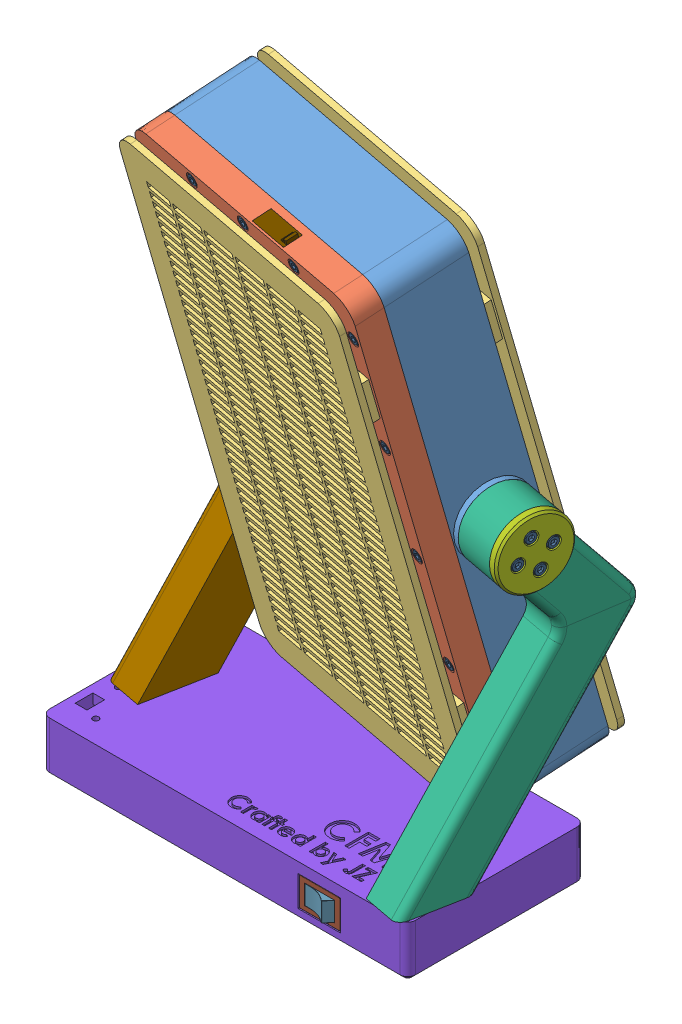
SolidWorks assembly assm, configuration Default. Lengths in mm.
Overall size (203.65 301.44 157.63).
57 component instances, 21 part files, 88 mates.
Components (placement in the parent):
- body-1: body [Default] at (119.8439 173.8656 72.5673) x (0.982382 0 0.186882) z (-0.180853 -0.251949 0.950691) size (182 260 42)
- cap-1: cap [Default] at (110.6204 161.0162 121.0525) x (-0.982382 0 -0.186882) z (0.180853 0.251949 -0.950691) size (140 260 13)
- cover-1: cover [Default] at (109.897 160.0084 124.8553) x (0.982382 0 0.186882) z (-0.180853 -0.251949 0.950691) size (140 260 12)
- Fan_120x120x38.step-1: Fan_120x120x38.step [Default] at (117.4629 232.8978 87.7588) x (0.982382 0 0.186882) z (-0.180853 -0.251949 0.950691) size (120 120 43.47)
  - Propeller.step-1: Propeller.step [Default] at (0 0 14.5) size (112.33 112.13 17.05)
  - Screws.step-1: Screws.step [Default] at origin size (116.5 116.5 11.47) (hidden)
  - LabelString.step-1: LabelString.step [Default] at origin size (29.77 5.26 0.01) (hidden)
  - Label.step-1: Label.step [Default] at origin size (38.43 38.43 0.1) (hidden)
  - Frame.step-1: Frame.step [Default] at origin size (120 120 38)
- Fan_120x120x38.step-2: Fan_120x120x38.step [Default] at (123.1131 116.7689 58.0576) x (0.982382 0 0.186882) z (-0.180853 -0.251949 0.950691) size (120 120 43.47)
  - Propeller.step-1: Propeller.step [Default] at (0 0 14.5) size (112.33 112.13 17.05)
  - Screws.step-1: Screws.step [Default] at origin size (116.5 116.5 11.47) (hidden)
  - LabelString.step-1: LabelString.step [Default] at origin size (29.77 5.26 0.01) (hidden)
  - Label.step-1: Label.step [Default] at origin size (38.43 38.43 0.1) (hidden)
  - Frame.step-1: Frame.step [Default] at origin size (120 120 38)
- side_bar-1: side_bar [Default] at (197.7646 26 107.0923) x (0.982382 0 0.186882) z (-0.186882 0 0.982382) size (20.38 160.33 105.41)
- tensioner-1: tensioner [Default] at (207.5884 168.8267 108.9611) x (0.180853 0.251949 -0.950691) z (0.982382 0 0.186882) size (35 35 4.6)
- bottom_upper-1: bottom_upper [Default] at (106.2737 0 117.6606) x (1 0 0) z (0 1 0) size (186 94 26)
- side_bar_irror-1: side_bar_irror [Default] at (34.6891 26 76.0699) x (0.982382 0 0.186882) z (-0.186882 0 0.982382) size (20.38 160.33 105.41)
- cover-2: cover [Default] at (120.5673 174.8734 68.7645) x (-0.982382 0 -0.186882) z (0.180853 0.251949 -0.950691) size (140 260 12)
- tensioner-2: tensioner [Default] at (24.8653 168.8267 74.2011) x (0.047085 -0.967741 -0.24751) z (-0.982382 0 -0.186882) size (35 35 4.6)
- socket head cap screw_am-5: socket head cap screw_am [B18.3.1M - 3 x 0.5 x 65 Hex SHCS -- 18NHX] at (19.4889 166.8111 81.0591) x (0.982382 0 0.186882) z (-0.179429 0.27958 0.943207) size (68 5.5 5.5)
- socket head cap screw_am-6: socket head cap screw_am [B18.3.1M - 3 x 0.5 x 65 Hex SHCS -- 18NHX] at (21.3124 161.0847 71.4735) x (0.982382 0 0.186882) z (-0.179429 0.27958 0.943207) size (68 5.5 5.5)
- socket head cap screw_am-7: socket head cap screw_am [B18.3.1M - 3 x 0.5 x 65 Hex SHCS -- 18NHX] at (22.3826 170.8422 65.8481) x (0.982382 0 0.186882) z (-0.179429 0.27958 0.943207) size (68 5.5 5.5)
- socket head cap screw_am-8: socket head cap screw_am [B18.3.1M - 3 x 0.5 x 65 Hex SHCS -- 18NHX] at (20.5591 176.5686 75.4337) x (0.982382 0 0.186882) z (-0.179429 0.27958 0.943207) size (68 5.5 5.5)
- socket head cap screw_am-9: socket head cap screw_am [B18.3.1M - 3 x 0.5 x 5 Hex SHCS -- 5NHX] at (211.1413 176.5686 111.6887) x (-0.982382 0 -0.186882) z (0.179429 -0.27958 -0.943207) size (8 5.5 5.5)
- socket head cap screw_am-10: socket head cap screw_am [B18.3.1M - 3 x 0.5 x 5 Hex SHCS -- 5NHX] at (212.9648 170.8422 102.1031) x (-0.982382 0 -0.186882) z (0.179429 -0.27958 -0.943207) size (8 5.5 5.5)
- socket head cap screw_am-11: socket head cap screw_am [B18.3.1M - 3 x 0.5 x 5 Hex SHCS -- 5NHX] at (211.8946 161.0847 107.7285) x (-0.982382 0 -0.186882) z (0.179429 -0.27958 -0.943207) size (8 5.5 5.5)
- socket head cap screw_am-12: socket head cap screw_am [B18.3.1M - 3 x 0.5 x 5 Hex SHCS -- 5NHX] at (210.0711 166.8111 117.3142) x (-0.982382 0 -0.186882) z (0.179429 -0.27958 -0.943207) size (8 5.5 5.5)
- socket head cap screw_am-13: socket head cap screw_am [B18.3.1M - 3 x 0.5 x 12 Hex SHCS -- 12NHX] at (72.8074 281.9838 145.9177) x (0.180853 0.251949 -0.950691) z (0.98351 -0.045912 0.174929) size (15 5.5 5.5)
- socket head cap screw_am-14: socket head cap screw_am [B18.3.1M - 3 x 0.5 x 12 Hex SHCS -- 12NHX] at (104.7348 281.9838 151.9913) x (0.180853 0.251949 -0.950691) z (0.98351 -0.045912 0.174929) size (15 5.5 5.5)
- socket head cap screw_am-15: socket head cap screw_am [B18.3.1M - 3 x 0.5 x 12 Hex SHCS -- 12NHX] at (136.6623 281.9838 158.065) x (0.180853 0.251949 -0.950691) z (0.98351 -0.045912 0.174929) size (15 5.5 5.5)
- socket head cap screw_am-16: socket head cap screw_am [B18.3.1M - 3 x 0.5 x 12 Hex SHCS -- 12NHX] at (169.296 267.4677 160.426) x (0.180853 0.251949 -0.950691) z (0.98351 -0.045912 0.174929) size (15 5.5 5.5)
- socket head cap screw_am-17: socket head cap screw_am [B18.3.1M - 3 x 0.5 x 12 Hex SHCS -- 12NHX] at (171.8856 214.242 146.8129) x (0.180853 0.251949 -0.950691) z (0.98351 -0.045912 0.174929) size (15 5.5 5.5)
- socket head cap screw_am-18: socket head cap screw_am [B18.3.1M - 3 x 0.5 x 12 Hex SHCS -- 12NHX] at (174.4753 161.0162 133.1998) x (0.180853 0.251949 -0.950691) z (0.98351 -0.045912 0.174929) size (15 5.5 5.5)
- socket head cap screw_am-19: socket head cap screw_am [B18.3.1M - 3 x 0.5 x 12 Hex SHCS -- 12NHX] at (177.0649 107.7905 119.5868) x (0.180853 0.251949 -0.950691) z (0.98351 -0.045912 0.174929) size (15 5.5 5.5)
- socket head cap screw_am-20: socket head cap screw_am [B18.3.1M - 3 x 0.5 x 12 Hex SHCS -- 12NHX] at (179.6546 54.5648 105.9737) x (0.180853 0.251949 -0.950691) z (0.98351 -0.045912 0.174929) size (15 5.5 5.5)
- socket head cap screw_am-21: socket head cap screw_am [B18.3.1M - 3 x 0.5 x 12 Hex SHCS -- 12NHX] at (148.4334 40.0487 96.1874) x (0.180853 0.251949 -0.950691) z (0.98351 -0.045912 0.174929) size (15 5.5 5.5)
- socket head cap screw_am-22: socket head cap screw_am [B18.3.1M - 3 x 0.5 x 12 Hex SHCS -- 12NHX] at (116.506 40.0487 90.1138) x (0.180853 0.251949 -0.950691) z (0.98351 -0.045912 0.174929) size (15 5.5 5.5)
- socket head cap screw_am-23: socket head cap screw_am [B18.3.1M - 3 x 0.5 x 12 Hex SHCS -- 12NHX] at (84.5785 40.0487 84.0401) x (0.180853 0.251949 -0.950691) z (0.98351 -0.045912 0.174929) size (15 5.5 5.5)
- socket head cap screw_am-24: socket head cap screw_am [B18.3.1M - 3 x 0.5 x 12 Hex SHCS -- 12NHX] at (51.9449 54.5648 81.6791) x (0.180853 0.251949 -0.950691) z (0.98351 -0.045912 0.174929) size (15 5.5 5.5)
- socket head cap screw_am-25: socket head cap screw_am [B18.3.1M - 3 x 0.5 x 12 Hex SHCS -- 12NHX] at (49.3552 107.7905 95.2922) x (0.180853 0.251949 -0.950691) z (0.98351 -0.045912 0.174929) size (15 5.5 5.5)
- socket head cap screw_am-26: socket head cap screw_am [B18.3.1M - 3 x 0.5 x 12 Hex SHCS -- 12NHX] at (46.7655 161.0162 108.9052) x (0.180853 0.251949 -0.950691) z (0.98351 -0.045912 0.174929) size (15 5.5 5.5)
- socket head cap screw_am-27: socket head cap screw_am [B18.3.1M - 3 x 0.5 x 12 Hex SHCS -- 12NHX] at (44.1759 214.242 122.5183) x (0.180853 0.251949 -0.950691) z (0.98351 -0.045912 0.174929) size (15 5.5 5.5)
- socket head cap screw_am-28: socket head cap screw_am [B18.3.1M - 3 x 0.5 x 12 Hex SHCS -- 12NHX] at (41.5862 267.4677 136.1314) x (0.180853 0.251949 -0.950691) z (0.98351 -0.045912 0.174929) size (15 5.5 5.5)
- socket head cap screw_am-29: socket head cap screw_am [B18.3.1M - 3 x 0.5 x 12 Hex SHCS -- 12NHX] at (90.9728 161.0162 117.3149) x (0.180853 0.251949 -0.950691) z (0.98351 -0.045912 0.174929) size (15 5.5 5.5)
- socket head cap screw_am-30: socket head cap screw_am [B18.3.1M - 3 x 0.5 x 12 Hex SHCS -- 12NHX] at (130.2681 161.0162 124.7902) x (0.180853 0.251949 -0.950691) z (0.98351 -0.045912 0.174929) size (15 5.5 5.5)
- Power Switch.step-1: Power Switch.step [Default] at (143.8457 5.541 160.3606) x (1 0 0) z (0 -1 0) size (21.33 24.14 14.86)
  - Power Switch1.STEP-1: Power Switch1.STEP [Default] at origin size (21.33 13.56 14.86)
  - Power Switch2.STEP-1: Power Switch2.STEP [Default] at origin size (0.83 7.82 7.65)
  - Power Switch3.STEP-1: Power Switch3.STEP [Default] at origin size (0.83 7.82 7.65)
  - Power Switch4.STEP-1: Power Switch4.STEP [Default] at origin size (15.06 5.51 9.8)
- Fuse.step-1: Fuse.step [Default] at (159.2737 13 88.8606) x (-0.999964 -0.008477 0) z (0 0 -1) size (15 15.01 38.3)
  - Fuse1.STEP-1: Fuse1.STEP [Default] at origin size (4 2.2 7.9)
  - Fuse2.STEP-1: Fuse2.STEP [Default] at origin size (15 15.01 38.3)
- cable-1: cable [Default] at (33.2737 13 68.6606) size (39.97 7 53.33)
- carbon_filling_cap-1: carbon_filling_cap [Default] at (121.7053 287.1775 151.0738) x (-0.982382 0 -0.186882) z (-0.047085 0.967741 0.24751) size (23.5 8.5 11.9)
Mates (geometry in assembly coordinates):
- Concentric1: concentric aligned: cylinder of body-1 through (172.0811 271.3477 145.7853) axis (-0.180853 -0.251949 0.950691) radius 2.2; cylinder of cap-1 through (169.296 267.4677 160.426) axis (-0.180853 -0.251949 0.950691) radius 3.25
- Concentric2: concentric aligned: cylinder of body-1 through (54.73 58.4448 67.0385) axis (-0.180853 -0.251949 0.950691) radius 2.2; cylinder of cap-1 through (51.9449 54.5648 81.6791) axis (-0.180853 -0.251949 0.950691) radius 3.25
- Coincident1: coincident aligned: plane of cap-1 through (187.1358 37.4775 93.4017) normal (0.982382 0 0.186882); plane of cover-1 through (183.1571 31.9346 114.3169) normal (0.982382 0 0.186882)
- Coincident2: coincident aligned: plane of cap-1 through (174.8939 289.0901 157.7543) normal (-0.047085 0.967741 0.24751); plane of cover-1 through (33.3816 283.5472 152.5061) normal (-0.047085 0.967741 0.24751)
- Coincident5: coincident anti-aligned: plane of body-1 through (47.1167 280.3804 131.1387) normal (0.047085 -0.967741 -0.24751); plane of Fan_120x120x38.step-1/Frame.step-1 through (111.1874 286.1553 120.7477) normal (-0.047085 0.967741 0.24751)
- Coincident6: coincident anti-aligned: plane of body-1 through (165.985 280.3804 153.7514) normal (-0.982382 0 -0.186882); plane of Fan_120x120x38.step-1/Frame.step-1 through (172.9554 228.0909 117.1099) normal (0.982382 0 0.186882)
- Coincident7: coincident anti-aligned: plane of body-1 through (112.9715 164.2916 108.6936) normal (0.180853 0.251949 -0.950691); plane of Fan_120x120x38.step-1/Frame.step-1 through (110.5905 223.3238 123.8851) normal (-0.180853 -0.251949 0.950691)
- Coincident8: coincident anti-aligned: plane of cap-1 through (110.6204 161.0162 121.0525) normal (-0.180853 -0.251949 0.950691); plane of cover-1 through (173.291 249.9516 156.5439) normal (0.180853 0.251949 -0.950691)
- Concentric7: concentric anti-aligned: cylinder of body-1 through (205.6236 168.8267 108.5873) axis (-0.982382 0 -0.186882) radius 12; cylinder of side_bar-1 through (187.9408 168.8267 105.2235) axis (0.982382 0 0.186882) radius 17.5
- Coincident9: coincident anti-aligned: plane of body-1 through (187.9408 168.8267 105.2235) normal (0.982382 0 0.186882); plane of side_bar-1 through (188.8609 185.6198 100.3868) normal (-0.982382 0 -0.186882)
- Concentric9: concentric aligned: cylinder of body-1 through (198.3703 176.5686 109.2592) axis (0.982382 0 0.186882) radius 2.2; cylinder of tensioner-1 through (211.1413 176.5686 111.6887) axis (0.982382 0 0.186882) radius 3.25
- Concentric10: concentric aligned: cylinder of body-1 through (199.1236 161.0847 105.2991) axis (0.982382 0 0.186882) radius 2.2; cylinder of tensioner-1 through (211.8946 161.0847 107.7285) axis (0.982382 0 0.186882) radius 3.25
- Coincident10: coincident anti-aligned: plane of side_bar-1 through (208.5085 185.6198 104.1244) normal (0.982382 0 0.186882); plane of tensioner-1 through (207.5884 168.8267 108.9611) normal (-0.982382 0 -0.186882)
- Coincident11: coincident anti-aligned: plane of body-1 through (177.5646 48.1627 90.2052) normal (-0.180853 -0.251949 0.950691); plane of cap-1 through (177.5646 48.1627 90.2052) normal (0.180853 0.251949 -0.950691)
- Concentric13: concentric aligned: cylinder of side_bar-1 through (183.2737 32.5 151.1606) axis (0 -1 0) radius 2.2; cylinder of bottom_upper-1 through (183.2737 21 151.1606) axis (0 -1 0) radius 1.5
- Coincident13: coincident anti-aligned: plane of side_bar-1 through (197.7646 26 107.0923) normal (0 -1 0); plane of bottom_upper-1 through (106.2737 26 117.6606) normal (0 1 0)
- Concentric15: concentric: cylinder of body-1 through (26.83 168.8267 74.5749) axis (0.982382 0 0.186882) radius 12; cylinder of side_bar_irror-1 through (-8.6168 168.8267 67.8317) axis (0.982382 0 0.186882) radius 12.05
- Coincident14: coincident anti-aligned: plane of body-1 through (44.5129 168.8267 77.9388) normal (-0.982382 0 -0.186882); plane of side_bar_irror-1 through (45.433 185.6198 73.1021) normal (0.982382 0 0.186882)
- Coincident15: coincident anti-aligned: plane of bottom_upper-1 through (106.2737 26 117.6606) normal (0 1 0); plane of side_bar_irror-1 through (34.6891 26 76.0699) normal (0 -1 0)
- Coincident16: coincident anti-aligned: plane of body-1 through (119.8439 173.8656 72.5673) normal (0.180853 0.251949 -0.950691); plane of cover-2 through (182.5145 262.801 108.0586) normal (-0.180853 -0.251949 0.950691)
- Coincident17: coincident aligned: plane of body-1 through (37.3603 289.0901 131.5909) normal (-0.047085 0.967741 0.24751); plane of cover-2 through (184.8408 302.9472 105.4663) normal (-0.047085 0.967741 0.24751)
- Coincident18: coincident aligned: plane of body-1 through (174.8939 289.0901 157.7543) normal (0.982382 0 0.186882); plane of cover-2 through (197.0828 51.3347 41.1137) normal (0.982382 0 0.186882)
- Concentric16: concentric aligned: cylinder of body-1 through (33.33 176.5686 77.8631) axis (-0.982382 0 -0.186882) radius 2.2; cylinder of tensioner-2 through (20.5591 176.5686 75.4337) axis (-0.982382 0 -0.186882) radius 3.25
- Concentric17: concentric aligned: cylinder of body-1 through (34.0834 161.0847 73.903) axis (-0.982382 0 -0.186882) radius 2.2; cylinder of tensioner-2 through (21.3124 161.0847 71.4735) axis (-0.982382 0 -0.186882) radius 3.25
- Coincident19: coincident anti-aligned: plane of side_bar_irror-1 through (25.7854 185.6198 69.3644) normal (-0.982382 0 -0.186882); plane of tensioner-2 through (24.8653 168.8267 74.2011) normal (0.982382 0 0.186882)
- Concentric181: concentric aligned: cylinder of tensioner-2 through (19.4889 166.8111 81.0591) axis (-0.982382 0 -0.186882) radius 1.6; cylinder of socket head cap screw_am-5 through (-11.7017 166.8111 75.1256) axis (-0.982382 0 -0.186882) radius 1.5
- Coincident211: coincident anti-aligned: plane of tensioner-2 through (22.5114 165.2627 81.2238) normal (-0.982382 0 -0.186882); plane of socket head cap screw_am-5 through (22.5798 169.4514 80.8645) normal (0.982382 0 0.186882)
- Concentric191: concentric aligned: cylinder of tensioner-2 through (21.3124 161.0847 71.4735) axis (-0.982382 0 -0.186882) radius 1.6; cylinder of socket head cap screw_am-6 through (-9.8782 161.0847 65.54) axis (-0.982382 0 -0.186882) radius 1.5
- Coincident221: coincident anti-aligned: plane of tensioner-2 through (24.3349 159.5363 71.6382) normal (-0.982382 0 -0.186882); plane of socket head cap screw_am-6 through (24.4033 163.7251 71.2789) normal (0.982382 0 0.186882)
- Concentric201: concentric aligned: cylinder of tensioner-2 through (22.3826 170.8422 65.8481) axis (-0.982382 0 -0.186882) radius 1.6; cylinder of socket head cap screw_am-7 through (-8.8081 170.8422 59.9146) axis (-0.982382 0 -0.186882) radius 1.5
- Coincident231: coincident anti-aligned: plane of tensioner-2 through (25.4051 169.2939 66.0127) normal (-0.982382 0 -0.186882); plane of socket head cap screw_am-7 through (25.4734 173.4826 65.6534) normal (0.982382 0 0.186882)
- Concentric211: concentric aligned: cylinder of tensioner-2 through (20.5591 176.5686 75.4337) axis (-0.982382 0 -0.186882) radius 1.6; cylinder of socket head cap screw_am-8 through (-10.6316 176.5686 69.5002) axis (-0.982382 0 -0.186882) radius 1.5
- Coincident241: coincident anti-aligned: plane of tensioner-2 through (23.5816 175.0202 75.5983) normal (-0.982382 0 -0.186882); plane of socket head cap screw_am-8 through (23.6499 179.2089 75.239) normal (0.982382 0 0.186882)
- Concentric221: concentric aligned: cylinder of tensioner-1 through (211.1413 176.5686 111.6887) axis (0.982382 0 0.186882) radius 1.6; cylinder of socket head cap screw_am-9 through (242.3319 176.5686 117.6222) axis (0.982382 0 0.186882) radius 1.5
- Coincident251: coincident anti-aligned: plane of tensioner-1 through (208.4835 176.9717 109.607) normal (0.982382 0 0.186882); plane of socket head cap screw_am-9 through (208.3378 179.2089 110.3728) normal (-0.982382 0 -0.186882)
- Concentric231: concentric aligned: cylinder of tensioner-1 through (212.9648 170.8422 102.1031) axis (0.982382 0 0.186882) radius 1.6; cylinder of socket head cap screw_am-10 through (244.1554 170.8422 108.0366) axis (0.982382 0 0.186882) radius 1.5
- Coincident261: coincident anti-aligned: plane of tensioner-1 through (210.307 171.2454 100.0213) normal (0.982382 0 0.186882); plane of socket head cap screw_am-10 through (210.1613 173.4826 100.7872) normal (-0.982382 0 -0.186882)
- Concentric241: concentric aligned: cylinder of tensioner-1 through (211.8946 161.0847 107.7285) axis (0.982382 0 0.186882) radius 1.6; cylinder of socket head cap screw_am-11 through (243.0853 161.0847 113.662) axis (0.982382 0 0.186882) radius 1.5
- Coincident271: coincident anti-aligned: plane of tensioner-1 through (209.2368 161.4879 105.6468) normal (0.982382 0 0.186882); plane of socket head cap screw_am-11 through (209.0912 163.7251 106.4126) normal (-0.982382 0 -0.186882)
- Concentric251: concentric aligned: cylinder of tensioner-1 through (210.0711 166.8111 117.3142) axis (0.982382 0 0.186882) radius 1.6; cylinder of socket head cap screw_am-12 through (241.2618 166.8111 123.2476) axis (0.982382 0 0.186882) radius 1.5
- Coincident281: coincident anti-aligned: plane of tensioner-1 through (207.4133 167.2142 115.2324) normal (0.982382 0 0.186882); plane of socket head cap screw_am-12 through (207.2677 169.4514 115.9982) normal (-0.982382 0 -0.186882)
- Concentric261: concentric aligned: cylinder of cap-1 through (72.8074 281.9838 145.9177) axis (-0.180853 -0.251949 0.950691) radius 1.6; cylinder of socket head cap screw_am-13 through (67.0653 273.9844 176.1021) axis (-0.180853 -0.251949 0.950691) radius 1.5
- Coincident291: coincident anti-aligned: plane of cap-1 through (71.7781 282.7397 142.7666) normal (-0.180853 -0.251949 0.950691); plane of socket head cap screw_am-13 through (73.3488 285.3979 143.7699) normal (0.180853 0.251949 -0.950691)
- Concentric271: concentric aligned: cylinder of cap-1 through (104.7348 281.9838 151.9913) axis (-0.180853 -0.251949 0.950691) radius 1.6; cylinder of socket head cap screw_am-14 through (98.9928 273.9844 182.1758) axis (-0.180853 -0.251949 0.950691) radius 1.5
- Coincident301: coincident anti-aligned: plane of cap-1 through (103.7056 282.7397 148.8402) normal (-0.180853 -0.251949 0.950691); plane of socket head cap screw_am-14 through (105.2762 285.3979 149.8435) normal (0.180853 0.251949 -0.950691)
- Concentric281: concentric aligned: cylinder of cap-1 through (136.6623 281.9838 158.065) axis (-0.180853 -0.251949 0.950691) radius 1.6; cylinder of socket head cap screw_am-15 through (130.9202 273.9844 188.2494) axis (-0.180853 -0.251949 0.950691) radius 1.5
- Coincident311: coincident anti-aligned: plane of cap-1 through (135.633 282.7397 154.9139) normal (-0.180853 -0.251949 0.950691); plane of socket head cap screw_am-15 through (137.2037 285.3979 155.9172) normal (0.180853 0.251949 -0.950691)
- Concentric291: concentric aligned: cylinder of cap-1 through (169.296 267.4677 160.426) axis (-0.180853 -0.251949 0.950691) radius 1.6; cylinder of socket head cap screw_am-16 through (163.5539 259.4683 190.6104) axis (-0.180853 -0.251949 0.950691) radius 1.5
- Coincident321: coincident anti-aligned: plane of cap-1 through (168.2667 268.2236 157.2749) normal (-0.180853 -0.251949 0.950691); plane of socket head cap screw_am-16 through (169.8374 270.8818 158.2782) normal (0.180853 0.251949 -0.950691)
- Concentric301: concentric aligned: cylinder of cap-1 through (171.8856 214.242 146.8129) axis (-0.180853 -0.251949 0.950691) radius 1.6; cylinder of socket head cap screw_am-17 through (166.1435 206.2426 176.9974) axis (-0.180853 -0.251949 0.950691) radius 1.5
- Coincident331: coincident anti-aligned: plane of cap-1 through (170.8564 214.9978 143.6618) normal (-0.180853 -0.251949 0.950691); plane of socket head cap screw_am-17 through (172.427 217.6561 144.6651) normal (0.180853 0.251949 -0.950691)
- Concentric311: concentric aligned: cylinder of cap-1 through (174.4753 161.0162 133.1998) axis (-0.180853 -0.251949 0.950691) radius 1.6; cylinder of socket head cap screw_am-18 through (168.7332 153.0169 163.3843) axis (-0.180853 -0.251949 0.950691) radius 1.5
- Coincident341: coincident anti-aligned: plane of cap-1 through (173.446 161.7721 130.0488) normal (-0.180853 -0.251949 0.950691); plane of socket head cap screw_am-18 through (175.0167 164.4304 131.052) normal (0.180853 0.251949 -0.950691)
- Concentric321: concentric aligned: cylinder of cap-1 through (177.0649 107.7905 119.5868) axis (-0.180853 -0.251949 0.950691) radius 1.6; cylinder of socket head cap screw_am-19 through (171.3228 99.7911 149.7712) axis (-0.180853 -0.251949 0.950691) radius 1.5
- Coincident351: coincident anti-aligned: plane of cap-1 through (176.0357 108.5464 116.4357) normal (-0.180853 -0.251949 0.950691); plane of socket head cap screw_am-19 through (177.6063 111.2046 117.439) normal (0.180853 0.251949 -0.950691)
- Concentric331: concentric aligned: cylinder of cap-1 through (179.6546 54.5648 105.9737) axis (-0.180853 -0.251949 0.950691) radius 1.6; cylinder of socket head cap screw_am-20 through (173.9125 46.5654 136.1582) axis (-0.180853 -0.251949 0.950691) radius 1.5
- Coincident361: coincident anti-aligned: plane of cap-1 through (178.6253 55.3206 102.8227) normal (-0.180853 -0.251949 0.950691); plane of socket head cap screw_am-20 through (180.196 57.9789 103.8259) normal (0.180853 0.251949 -0.950691)
- Concentric341: concentric aligned: cylinder of cap-1 through (148.4334 40.0487 96.1874) axis (-0.180853 -0.251949 0.950691) radius 1.6; cylinder of socket head cap screw_am-21 through (142.6913 32.0493 126.3719) axis (-0.180853 -0.251949 0.950691) radius 1.5
- Coincident371: coincident anti-aligned: plane of cap-1 through (147.4042 40.8045 93.0364) normal (-0.180853 -0.251949 0.950691); plane of socket head cap screw_am-21 through (148.9748 43.4628 94.0396) normal (0.180853 0.251949 -0.950691)
- Concentric351: concentric aligned: cylinder of cap-1 through (116.506 40.0487 90.1138) axis (-0.180853 -0.251949 0.950691) radius 1.6; cylinder of socket head cap screw_am-22 through (110.7639 32.0493 120.2982) axis (-0.180853 -0.251949 0.950691) radius 1.5
- Coincident381: coincident anti-aligned: plane of cap-1 through (115.4767 40.8045 86.9627) normal (-0.180853 -0.251949 0.950691); plane of socket head cap screw_am-22 through (117.0474 43.4628 87.966) normal (0.180853 0.251949 -0.950691)
- Concentric361: concentric aligned: cylinder of cap-1 through (84.5785 40.0487 84.0401) axis (-0.180853 -0.251949 0.950691) radius 1.6; cylinder of socket head cap screw_am-23 through (78.8365 32.0493 114.2246) axis (-0.180853 -0.251949 0.950691) radius 1.5
- Coincident391: coincident anti-aligned: plane of cap-1 through (83.5493 40.8045 80.8891) normal (-0.180853 -0.251949 0.950691); plane of socket head cap screw_am-23 through (85.1199 43.4628 81.8923) normal (0.180853 0.251949 -0.950691)
- Concentric371: concentric aligned: cylinder of cap-1 through (51.9449 54.5648 81.6791) axis (-0.180853 -0.251949 0.950691) radius 1.6; cylinder of socket head cap screw_am-24 through (46.2028 46.5654 111.8636) axis (-0.180853 -0.251949 0.950691) radius 1.5
- Coincident401: coincident anti-aligned: plane of cap-1 through (50.9156 55.3206 78.5281) normal (-0.180853 -0.251949 0.950691); plane of socket head cap screw_am-24 through (52.4862 57.9789 79.5313) normal (0.180853 0.251949 -0.950691)
- Concentric381: concentric aligned: cylinder of cap-1 through (49.3552 107.7905 95.2922) axis (-0.180853 -0.251949 0.950691) radius 1.6; cylinder of socket head cap screw_am-25 through (43.6131 99.7911 125.4766) axis (-0.180853 -0.251949 0.950691) radius 1.5
- Coincident411: coincident anti-aligned: plane of cap-1 through (48.3259 108.5464 92.1411) normal (-0.180853 -0.251949 0.950691); plane of socket head cap screw_am-25 through (49.8966 111.2046 93.1444) normal (0.180853 0.251949 -0.950691)
- Concentric391: concentric aligned: cylinder of cap-1 through (46.7655 161.0162 108.9052) axis (-0.180853 -0.251949 0.950691) radius 1.6; cylinder of socket head cap screw_am-26 through (41.0235 153.0169 139.0897) axis (-0.180853 -0.251949 0.950691) radius 1.5
- Coincident421: coincident anti-aligned: plane of cap-1 through (45.7363 161.7721 105.7542) normal (-0.180853 -0.251949 0.950691); plane of socket head cap screw_am-26 through (47.3069 164.4304 106.7574) normal (0.180853 0.251949 -0.950691)
- Concentric401: concentric aligned: cylinder of cap-1 through (44.1759 214.242 122.5183) axis (-0.180853 -0.251949 0.950691) radius 1.6; cylinder of socket head cap screw_am-27 through (38.4338 206.2426 152.7028) axis (-0.180853 -0.251949 0.950691) radius 1.5
- Coincident431: coincident anti-aligned: plane of cap-1 through (43.1466 214.9978 119.3672) normal (-0.180853 -0.251949 0.950691); plane of socket head cap screw_am-27 through (44.7173 217.6561 120.3705) normal (0.180853 0.251949 -0.950691)
- Concentric411: concentric aligned: cylinder of cap-1 through (41.5862 267.4677 136.1314) axis (-0.180853 -0.251949 0.950691) radius 1.6; cylinder of socket head cap screw_am-28 through (35.8442 259.4683 166.3158) axis (-0.180853 -0.251949 0.950691) radius 1.5
- Coincident441: coincident anti-aligned: plane of cap-1 through (40.557 268.2236 132.9803) normal (-0.180853 -0.251949 0.950691); plane of socket head cap screw_am-28 through (42.1276 270.8818 133.9836) normal (0.180853 0.251949 -0.950691)
- Concentric421: concentric aligned: cylinder of cap-1 through (90.9728 161.0162 117.3149) axis (-0.180853 -0.251949 0.950691) radius 1.6; cylinder of socket head cap screw_am-29 through (85.2307 153.0169 147.4994) axis (-0.180853 -0.251949 0.950691) radius 1.5
- Coincident451: coincident anti-aligned: plane of cap-1 through (89.9435 161.7721 114.1638) normal (-0.180853 -0.251949 0.950691); plane of socket head cap screw_am-29 through (91.5141 164.4304 115.1671) normal (0.180853 0.251949 -0.950691)
- Concentric431: concentric aligned: cylinder of cap-1 through (130.2681 161.0162 124.7902) axis (-0.180853 -0.251949 0.950691) radius 1.6; cylinder of socket head cap screw_am-30 through (124.526 153.0169 154.9746) axis (-0.180853 -0.251949 0.950691) radius 1.5
- Coincident461: coincident anti-aligned: plane of cap-1 through (129.2388 161.7721 121.6391) normal (-0.180853 -0.251949 0.950691); plane of socket head cap screw_am-30 through (130.8094 164.4304 122.6424) normal (0.180853 0.251949 -0.950691)
- Coincident47: coincident anti-aligned: plane of bottom_upper-1 through (106.2737 0 160.3606) normal (0 0 1); plane of Power Switch.step-1/Power Switch1.STEP-1 through (143.8457 5.541 160.3606) normal (0 0 -1)
- Distance1: distance = 5.6 mm aligned: plane of Power Switch.step-1/Power Switch1.STEP-1 through (143.8457 20.4 162.4307) normal (0 1 0); plane of bottom_upper-1 through (106.2737 26 117.6606) normal (0 1 0)
- Distance2: distance = 0.3 mm anti-aligned: plane of Power Switch.step-1/Power Switch1.STEP-1 through (164.6737 5.541 162.4307) normal (1 0 0); plane of bottom_upper-1 through (164.9737 20.7 160.3606) normal (-1 0 0)
- Concentric44: concentric anti-aligned: cylinder of bottom_upper-1 through (159.2737 13 86.6606) axis (0 0 -1) radius 8.4; cylinder of Fuse.step-1/Fuse2.STEP-1 through (159.2737 13 88.8606) axis (0 0 1) radius 7.1
- Coincident50: coincident aligned: plane of bottom_upper-1 through (13.2737 26 72.6606) normal (0 0 -1); plane of Fuse.step-1/Fuse2.STEP-1 through (159.2737 13 72.6606) normal (0 0 -1)
- Coincident53: coincident anti-aligned: plane of bottom_upper-1 through (190.2737 0 152.6606) normal (0 -1 0)
- Angle1: planar angle = 0.291253 rad: plane of cover-1 through (109.3544 159.2526 127.7074) normal (-0.180853 -0.251949 0.950691); plane of bottom_upper-1 through (13.2737 26 162.6606) normal (0 0 1)
- Angle4: planar angle = 2.276034 rad anti-aligned: plane of cover-1 through (109.3544 159.2526 127.7074) normal (-0.180853 -0.251949 0.950691); plane of side_bar-1 through (190.7436 129.5377 90.4898) normal (-0.153084 0.573576 0.804721)
- Coincident462: coincident aligned: plane of cap-1 through (174.8939 289.0901 157.7543) normal (-0.047085 0.967741 0.24751); plane of carbon_filling_cap-1 through (121.6582 288.1452 151.3213) normal (-0.047085 0.967741 0.24751)
- Coincident463: coincident anti-aligned: plane of cap-1 through (130.7605 286.1067 156.983) normal (0.180853 0.251949 -0.950691); plane of carbon_filling_cap-1 through (130.7134 287.0745 157.2305) normal (-0.180853 -0.251949 0.950691)
- Coincident464: coincident anti-aligned: plane of cap-1 through (111.9962 273.904 148.6017) normal (0.982382 0 0.186882); plane of carbon_filling_cap-1 through (111.0657 287.0745 153.4929) normal (-0.982382 0 -0.186882)
